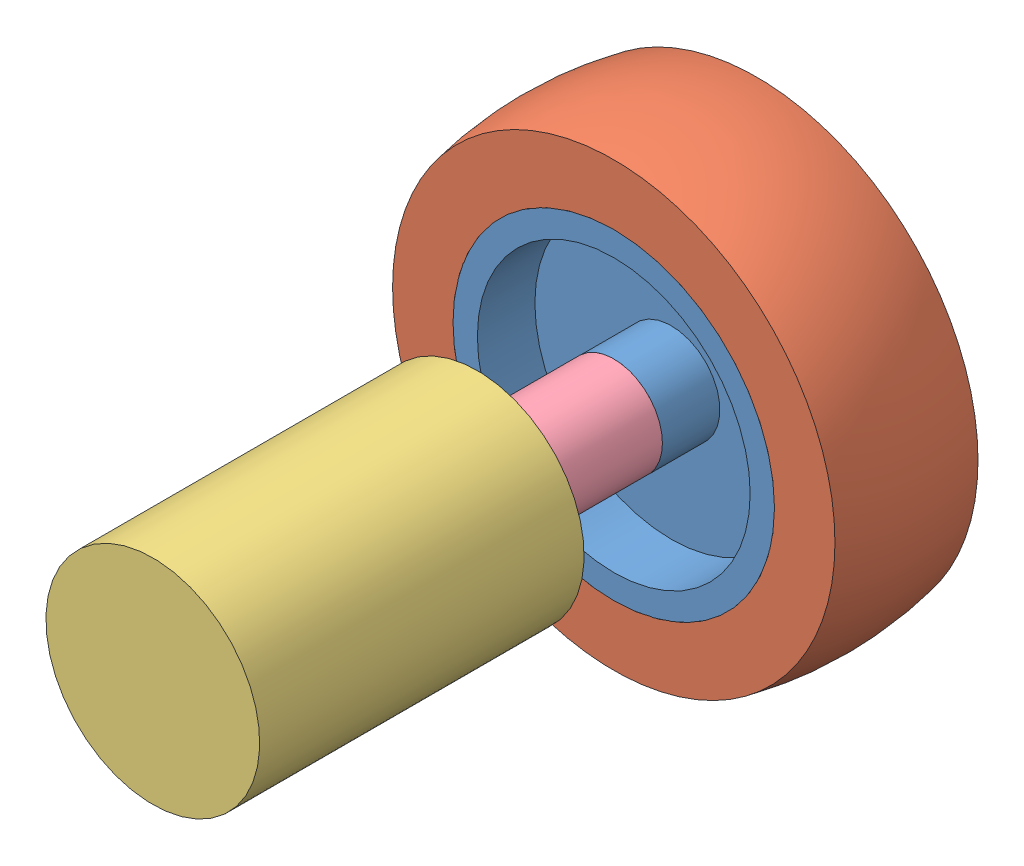
SolidWorks assembly Assem1, configuration Default. Lengths in mm.
Overall size (78.74 78.74 111.15).
5 component instances, 4 part files, 4 mates.
Components (placement in the parent):
- wheel_assem-1: wheel_assem [Default] at (38.1884 41.4621 55.5455) size (78.74 78.74 24.64)
  - wheel_inner-2: wheel_inner [Default] at origin size (55.37 55.37 24.64)
  - wheel_outter-1: wheel_outter [Default] at origin size (78.74 78.74 24.64)
- motor-1: motor [Default] at (38.1884 41.4621 91.3849) x (-0.936479 0.350723 0) z (0 0 -1) size (36.83 36.83 76.45)
- motor_to_wheel_adapter-1: motor_to_wheel_adapter [Default] at (38.1884 41.4621 67.8645) x (-0.396443 -0.918059 0) z (0 0 -1) size (16.76 16.76 48.67)
Mates (geometry in assembly coordinates):
- Concentric2: concentric aligned: cylinder of wheel_assem-1/wheel_inner-2 through (38.1884 41.4621 43.2265) axis (0 0 1) radius 3.175; cylinder of motor_to_wheel_adapter-1 through (38.1884 41.4621 36.1145) axis (0 0 1) radius 3.062
- Coincident2: coincident anti-aligned: plane of wheel_assem-1/wheel_inner-2 through (38.1884 41.4621 67.8645) normal (0 0 1); plane of motor_to_wheel_adapter-1 through (38.1884 41.4621 67.8645) normal (0 0 -1)
- Concentric3: concentric aligned: cylinder of motor-1 through (38.1884 41.4621 70.8109) axis (0 0 1) radius 2.9845; circle of motor_to_wheel_adapter-1
- Coincident3: coincident anti-aligned: plane of motor-1 through (38.1884 41.4621 70.8109) normal (0 0 -1); plane of motor_to_wheel_adapter-1 through (38.1884 41.4621 70.8109) normal (0 0 1)
